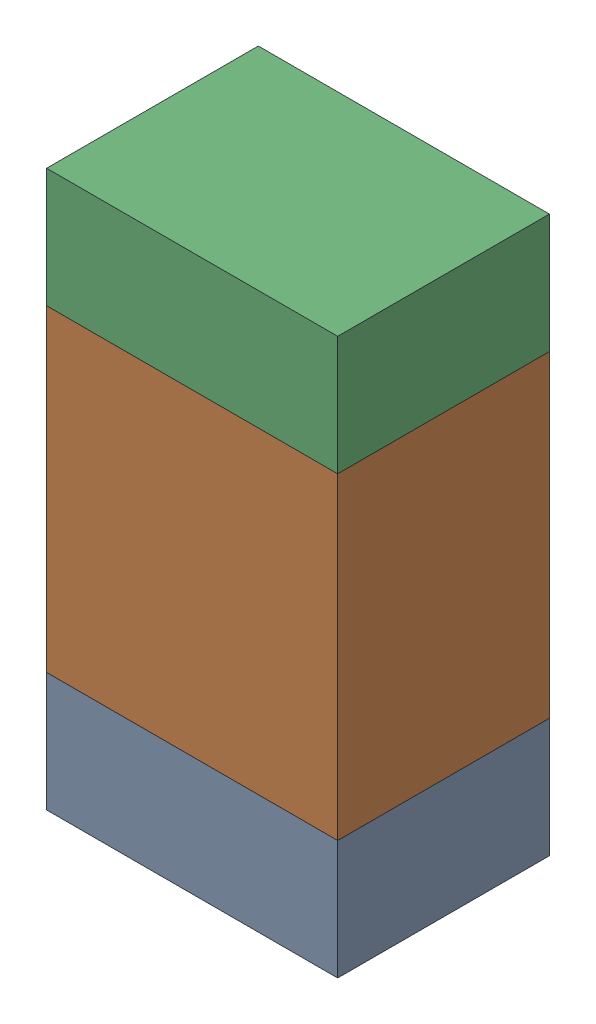
SolidWorks assembly R311_1PCB, configuration Default. Lengths in mm.
Overall size (0.55 1.05 0.4).
6 component instances, 2 part files, 0 mates.
Components (placement in the parent):
- 846483288-1: 846483288 [Default] at (126.2344 110.0374 -2.0638) size (0.55 0.22 0.4)
  - Extruded_12-1: Extruded_12 [Default] at origin size (0.55 0.22 0.4)
- 846483424-1: 846483424 [Default] at (126.2344 110.4499 -2.0638) size (0.55 0.6 0.4)
  - Extruded_13-1: Extruded_13 [Default] at origin size (0.55 0.6 0.4)
- 846483288-2: 846483288 [Default] at (126.2344 110.8624 -2.0638) size (0.55 0.22 0.4)
  - Extruded_12-1: Extruded_12 [Default] at origin size (0.55 0.22 0.4)
